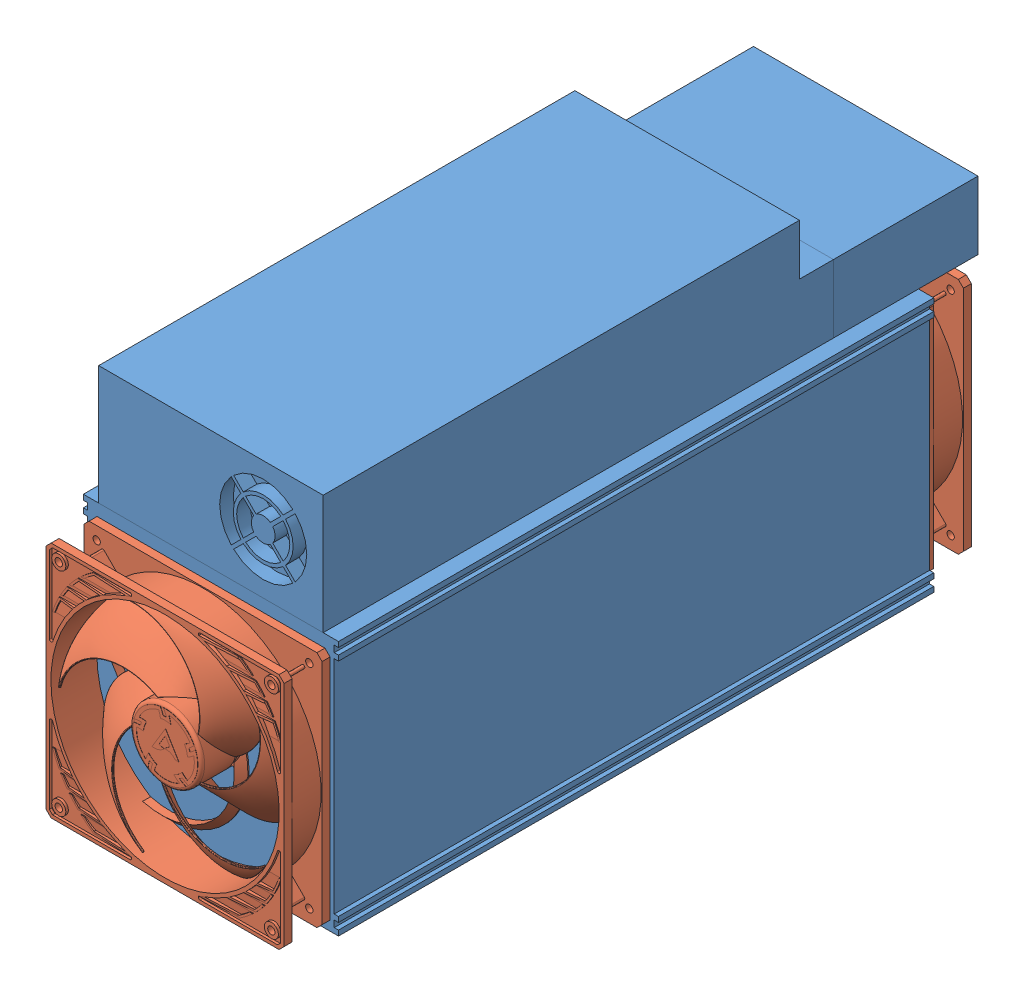
SolidWorks assembly Assem2, configuration Default. Lengths in mm.
Overall size (193.89 244.24 412).
3 component instances, 2 part files, 2 mates.
Components (placement in the parent):
- miner-1: miner [Default] at (11.1881 -61.7357 -145.24) size (150 220 385)
- arctic p14-1: arctic p14 [Default] at (-108.7779 -184.0702 204.76) size (193.81 193.81 27)
- arctic p14-3: arctic p14 [Default] at (-108.6945 -182.4446 -172.24) size (193.81 193.81 27)
Mates (geometry in assembly coordinates):
- Tangent1: tangent anti-aligned: plane of miner-1 through (11.1881 -61.7357 204.76) normal (0 0 1); face of arctic p14-1
- Tangent2: tangent anti-aligned: plane of miner-1 through (11.1881 -61.7357 -145.24) normal (0 0 -1); edge_curve of arctic p14-3
